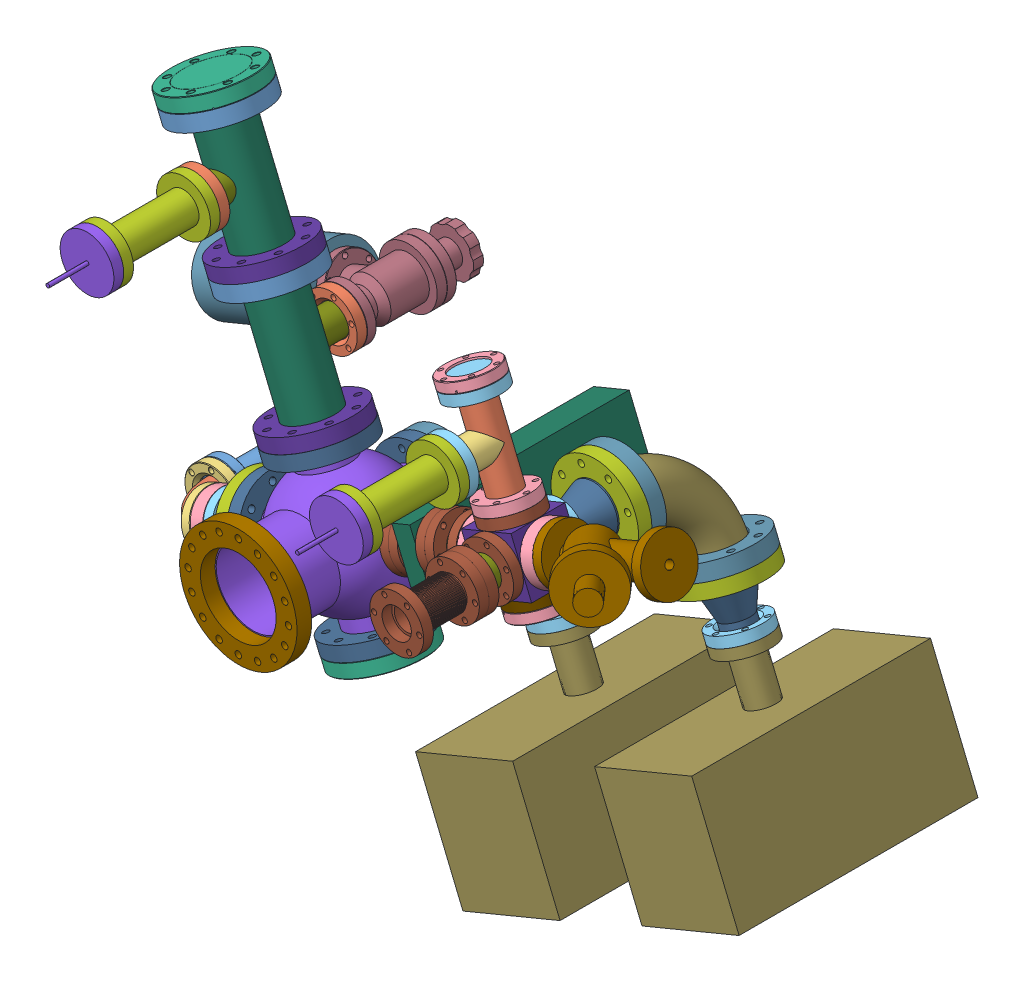
SolidWorks assembly Oven_BEC5_v2, configuration Default. Lengths in mm.
Overall size (747.25 862.61 620.88).
121 component instances, 43 part files, 72 mates.
Components (placement in the parent):
- mdc 275 halfnipple-1: mdc 275 halfnipple [Default] at (-24.8274 -18.3346 25.5574) size (69.34 69.34 62.48)
- L275-403502-6: L275-403502 [Default] at (27.1869 1.5159 24.2874) x (-0.923728 -0.383049 0) z (0 0 -1) size (77.27 39.99 77.27)
- 915002-3: 915002 [Default] at (-24.8274 -18.3346 38.2574) x (0 0 -1) z (1 0 0) size (12.7 69.34 69.34)
- mdc 2.75 doublesided_hole-1: mdc 2.75 doublesided_hole [Default] at (43.4775 8.648 79.5644) x (0.146727 -0.353833 -0.923728) z (0.923728 0.383049 0) size (69.34 69.34 19.05)
- 915002-4: 915002 [Default] at (14.1491 -3.5138 79.5644) x (0.923728 0.383049 0) z (0 0 1) size (12.7 69.34 69.34)
- 100014 (2.75 X 1.5 REC)-1: 100014 (2.75 X 1.5 REC) [Default] at (43.4775 8.648 79.5644) x (0.923728 0.383049 0) z (0 0 1) size (12.7 69.34 69.34)
- red1-402032-001-1: red1-402032-001 [Default] at (97.817 31.1814 79.5644) x (-0.923728 -0.383049 0) z (0 0 1) size (60.1 63.5 63.5)
- 110021 (4.5 X 2.5 NR)-1: 110021 (4.5 X 2.5 NR) [Default] at (97.817 31.1814 79.5644) x (-0.923728 -0.383049 0) z (0 0 1) size (17.27 113.54 113.54)
- custom_sixway_cross-1: custom_sixway_cross [Default] at (189.7246 79.077 65.1716) x (-0.923728 -0.383049 0) z (-0.383049 0.923728 0) size (201.17 247.4 209.3)
  - custom_sixway_tube-1: custom_sixway_tube [Default] at (-1.4041 14.3928 -9.0374) size (170.94 210.82 174.24)
  - 6in_CF_flange-3: 6in_CF_flange [Default] at (-1.4041 157.1408 -9.0374) x (1 0 0) z (0 -1 0) size (152.4 152.4 19.05)
  - 4.5in_CF_flange-1: 4.5in_CF_flange [Default] at (85.7179 14.3928 -9.0374) x (0 -1 0) z (0 0 1) size (114.3 17.53 114.3)
  - 4.5in_CF_flange-2: 4.5in_CF_flange [Default] at (-1.4041 14.3928 78.0846) x (1 0 0) z (0 -1 0) size (114.3 17.53 114.3)
  - 4.5in_CF_flange-3: 4.5in_CF_flange [Default] at (-1.4041 14.3928 -113.6854) x (1 0 0) z (0 -1 0) size (114.3 17.53 114.3)
  - 2.75in_CF_flange-1: 2.75in_CF_flange [Default] at (-97.9241 14.3928 -9.0374) x (0 -1 0) z (0 0 1) size (69.85 12.7 69.85)
  - 4.5in_CF_flange-4: 4.5in_CF_flange [Default] at (-1.4041 -90.2552 -9.0374) size (114.3 17.53 114.3)
- L4-403004_1-3: L4-403004_1 [Default] at (231.0174 -16.8357 -129.9856) x (0 0 1) z (-0.923728 -0.383049 0) size (161.67 161.67 113.54)
  - 403004-001_1-1: 403004-001_1 [Default] at origin size (128.92 128.92 67.08)
  - 100021 (4.5 X 2.5 R)_2-1: 100021 (4.5 X 2.5 R)_2 [Default] at (92.202 95.377 0) x (1 0 0) z (0 0 -1) size (19.05 113.54 113.54)
    - 100021 (4.5 X 2.5 INS)_2-1: 100021 (4.5 X 2.5 INS)_2 [Default] at origin size (12.04 82.3 82.3)
    - 100021 (4.5 X 2.5 REC)_2-1: 100021 (4.5 X 2.5 REC)_2 [Default] at (-6.35 0 0) x (1 0 0) z (0 0 -1) size (19.05 113.54 113.54)
  - 100021 (4.5 X 2.5 R)_2-2: 100021 (4.5 X 2.5 R)_2 [Default] at (0 3.175 0) x (0 -1 0) z (0 0 -1) size (19.05 113.54 113.54)
    - 100021 (4.5 X 2.5 INS)_2-1: 100021 (4.5 X 2.5 INS)_2 [Default] at origin size (12.04 82.3 82.3)
    - 100021 (4.5 X 2.5 REC)_2-1: 100021 (4.5 X 2.5 REC)_2 [Default] at (-6.35 0 0) x (1 0 0) z (0 0 -1) size (19.05 113.54 113.54)
- gatevalve-1: gatevalve [Default] at (298.9549 11.514 55.3656) x (0.383049 -0.923728 0) z (0.923728 0.383049 0) size (88.9 280.54 50.84)
  - gatevalve_body-1: gatevalve_body [Default] at (-95.213 2.8522 48.3049) size (88.9 277.88 50.04)
  - 2.75in_CF_flange-3: 2.75in_CF_flange [Default] at (-95.213 -24.1988 73.7492) x (1 0 0) z (0 1 0) size (69.85 12.7 69.85)
  - 2.75in_CF_flange-4: 2.75in_CF_flange [Default] at (-95.213 -24.1988 35.6049) x (-1 0 0) z (0 -1 0) size (69.85 12.7 69.85)
- minilength_nipple-1: minilength_nipple [Default] at (349.6703 127.2966 78.7528) x (0.383049 -0.923728 0) z (0 0 1) size (69.85 44.45 69.85)
  - minilength_nipple_tube-1: minilength_nipple_tube [Default] at (-7.6879 4.7765 0.8117) size (38.1 19.05 38.1)
  - 2.75in_CF_flange-3: 2.75in_CF_flange [Default] at (-7.6879 14.3015 0.8117) size (69.85 12.7 69.85)
  - 2.75in_CF_flange-4: 2.75in_CF_flange [Default] at (-7.6879 -17.4485 0.8117) size (69.85 12.7 69.85)
- mdc 2.75 doublesided_hole-4: mdc 2.75 doublesided_hole [Default] at (371.6676 144.741 79.5644) x (0.146727 -0.353833 0.923728) z (-0.923728 -0.383049 0) size (69.34 69.34 19.05)
- mdc 2.75 doublesided_hole-5: mdc 2.75 doublesided_hole [Default] at (453.787 178.7941 79.5644) x (0.146727 -0.353833 0.923728) z (-0.923728 -0.383049 0) size (69.34 69.34 19.05)
- six way cube-1: six way cube [Default] at (421.5258 165.4161 79.5644) x (0 0 1) z (-0.923728 -0.383049 0) size (69.85 69.85 69.85)
- 2.75in  window mdc-1: 2.75in  window mdc [Default] at (439.7685 121.4235 79.5644) x (0.853273 0.353833 0.383049) z (-0.383049 0.923728 0) size (69.34 69.34 12.7)
  - Part3^2.75in  window mdc-1: Part3^2.75in  window mdc [Default] at origin size (69.34 69.34 12.7) (virtual)
  - Part4^2.75in  window mdc-1: Part4^2.75in  window mdc [Default] at (0 0 12.7) size (38.1 38.1 2.67) (virtual)
- T275-404002_a-1: T275-404002_a [Default] at (357.4671 319.8944 79.5644) x (0.923728 0.383049 0) z (0.383049 -0.923728 0) size (69.34 97.13 124.92)
  - 404002-001-1: 404002-001 [Default] at origin size (38.1 38.1 114.3)
  - 404002-002-1: 404002-002 [Default] at (0 0 57.15) x (-1 0 0) z (0 1 0) size (38.1 38.1 58.53)
  - 110014 (2.75 X 1.5 NR)_1-1: 110014 (2.75 X 1.5 NR)_1 [Default] at (0 0 113.2586) x (0 0 1) z (-1 0 0) size (12.7 69.34 69.34)
  - 100014 (2.75 X 1.5 R)-1: 100014 (2.75 X 1.5 R) [Default] at (0 62.4586 57.15) x (0 -1 0) z (1 0 0) size (12.7 69.34 69.34)
    - 100014 (2.75 X 1.5 REC)_1-1: 100014 (2.75 X 1.5 REC)_1 [Default] at origin size (12.7 69.34 69.34)
    - 100014 (2.75 X 1.5 INS)-1: 100014 (2.75 X 1.5 INS) [Default] at (1.17 0 0) x (1 0 0) z (0 0.994423 -0.105464) size (6.96 48.1 48.1)
  - 100014 (2.75 X 1.5 R)-2: 100014 (2.75 X 1.5 R) [Default] at (0 0 -5.3086) x (0 0 1) z (-1 0 0) size (12.7 69.34 69.34)
    - 100014 (2.75 X 1.5 REC)_1-1: 100014 (2.75 X 1.5 REC)_1 [Default] at origin size (12.7 69.34 69.34)
    - 100014 (2.75 X 1.5 INS)-1: 100014 (2.75 X 1.5 INS) [Default] at (1.17 0 0) x (1 0 0) z (0 0.994423 -0.105464) size (6.96 48.1 48.1)
- 2.75in_CF_flange-1: 2.75in_CF_flange [Default] at (403.2831 209.4086 79.5644) x (-0.923728 -0.383049 0) z (0 0 1) size (69.85 12.7 69.85)
- nipple 2.75 mdc-2: nipple 2.75 mdc [Default] at (379.3584 267.1034 142.023) x (1 0 0) z (0 -1 0) size (69.85 125.22 69.85)
- ion gauge uhv 24p footprint-2: ion gauge uhv 24p footprint [Default] at (379.3584 267.1034 279.945) x (1 0 0) z (0 1 0) size (69.85 147.62 69.85)
- valve mdc inline all metal small-1: valve mdc inline all metal small [Default] at (470.2109 185.6047 79.5644) x (-0.383049 0.923728 0) z (0 0 -1) size (75.44 172.37 161.4)
- 402032-1: 402032 [Default] at (421.5258 165.4161 -20.7656) x (0 0 1) z (-1 0 0) size (74.93 113.54 113.54)
  - 402032-001-1: 402032-001 [Default] at origin size (60.1 63.5 63.5)
  - 110021 (4.5 X 2.5 NR)-1: 110021 (4.5 X 2.5 NR) [Default] at (-9.525 0 0) size (17.27 113.54 113.54)
  - 100014 (2.75 X 1.5 R)-1: 100014 (2.75 X 1.5 R) [Default] at (65.405 0 0) x (-1 0 0) z (0 0 -1) size (12.7 69.34 69.34)
    - 100014 (2.75 X 1.5 REC)_1-1: 100014 (2.75 X 1.5 REC)_1 [Default] at origin size (12.7 69.34 69.34)
    - 100014 (2.75 X 1.5 INS)-1: 100014 (2.75 X 1.5 INS) [Default] at (1.17 0 0) x (1 0 0) z (0 0.994423 -0.105464) size (6.96 48.1 48.1)
- L4-403004_1-4: L4-403004_1 [Default] at (421.5258 165.4161 -39.8156) x (0.383049 -0.923728 0) z (0.923728 0.383049 0) size (161.67 161.67 113.54)
  - 403004-001_1-1: 403004-001_1 [Default] at origin size (128.92 128.92 67.08)
  - 100021 (4.5 X 2.5 R)_2-1: 100021 (4.5 X 2.5 R)_2 [Default] at (92.202 95.377 0) x (1 0 0) z (0 0 -1) size (19.05 113.54 113.54)
    - 100021 (4.5 X 2.5 INS)_2-1: 100021 (4.5 X 2.5 INS)_2 [Default] at origin size (12.04 82.3 82.3)
    - 100021 (4.5 X 2.5 REC)_2-1: 100021 (4.5 X 2.5 REC)_2 [Default] at (-6.35 0 0) x (1 0 0) z (0 0 -1) size (19.05 113.54 113.54)
  - 100021 (4.5 X 2.5 R)_2-2: 100021 (4.5 X 2.5 R)_2 [Default] at (0 3.175 0) x (0 -1 0) z (0 0 -1) size (19.05 113.54 113.54)
    - 100021 (4.5 X 2.5 INS)_2-1: 100021 (4.5 X 2.5 INS)_2 [Default] at origin size (12.04 82.3 82.3)
    - 100021 (4.5 X 2.5 REC)_2-1: 100021 (4.5 X 2.5 REC)_2 [Default] at (-6.35 0 0) x (1 0 0) z (0 0 -1) size (19.05 113.54 113.54)
- minilength_nipple-2: minilength_nipple [Default] at (429.2137 166.2277 131.9379) x (1 0 0) z (0 -1 0) size (69.85 44.45 69.85)
  - minilength_nipple_tube-1: minilength_nipple_tube [Default] at (-7.6879 4.7765 0.8117) size (38.1 19.05 38.1)
  - 2.75in_CF_flange-3: 2.75in_CF_flange [Default] at (-7.6879 14.3015 0.8117) size (69.85 12.7 69.85)
  - 2.75in_CF_flange-4: 2.75in_CF_flange [Default] at (-7.6879 -17.4485 0.8117) size (69.85 12.7 69.85)
- Bellow_2.75in_CF-1: Bellow_2.75in_CF [Default] at (449.3378 155.3944 206.3015) x (1 0 0) z (0 1 0) size (96.68 84.96 96.68)
  - 2.75in_bellow_tube-1: 2.75in_bellow_tube [Default] at (-27.8121 6.8508 10.0217) size (43.18 63.5 43.18)
  - 2.75in_CF_flange-1: 2.75in_CF_flange [Default] at (-27.8121 47.3621 10.0217) x (-0.837169 0 -0.546944) z (-0.546944 0 0.837169) size (69.85 12.7 69.85)
  - 2.75in_CF_flange-2: 2.75in_CF_flange [Default] at (-27.8121 -24.8992 10.0217) x (-0.837169 0 -0.546944) z (-0.546944 0 0.837169) size (69.85 12.7 69.85)
- 404002-001_1-1: 404002-001_1 [Default] at (115.1337 -161.6135 43.2434)
- 402032-2: 402032 [Default] at (238.3145 -34.4327 -129.9856) x (0.383049 -0.923728 0) z (0 0 1) size (74.93 113.54 113.54)
  - 402032-001-1: 402032-001 [Default] at origin size (60.1 63.5 63.5)
  - 110021 (4.5 X 2.5 NR)-1: 110021 (4.5 X 2.5 NR) [Default] at (-9.525 0 0) size (17.27 113.54 113.54)
  - 100014 (2.75 X 1.5 R)-1: 100014 (2.75 X 1.5 R) [Default] at (65.405 0 0) x (-1 0 0) z (0 0 -1) size (12.7 69.34 69.34)
    - 100014 (2.75 X 1.5 REC)_1-1: 100014 (2.75 X 1.5 REC)_1 [Default] at origin size (12.7 69.34 69.34)
    - 100014 (2.75 X 1.5 INS)-1: 100014 (2.75 X 1.5 INS) [Default] at (1.17 0 0) x (1 0 0) z (0 0.994423 -0.105464) size (6.96 48.1 48.1)
- 402032-3: 402032 [Default] at (465.3569 59.7166 -135.1926) x (0.383049 -0.923728 0) z (0 0 1) size (74.93 113.54 113.54)
  - 402032-001-1: 402032-001 [Default] at origin size (60.1 63.5 63.5)
  - 110021 (4.5 X 2.5 NR)-1: 110021 (4.5 X 2.5 NR) [Default] at (-9.525 0 0) size (17.27 113.54 113.54)
  - 100014 (2.75 X 1.5 R)-1: 100014 (2.75 X 1.5 R) [Default] at (65.405 0 0) x (-1 0 0) z (0 0 -1) size (12.7 69.34 69.34)
    - 100014 (2.75 X 1.5 REC)_1-1: 100014 (2.75 X 1.5 REC)_1 [Default] at origin size (12.7 69.34 69.34)
    - 100014 (2.75 X 1.5 INS)-1: 100014 (2.75 X 1.5 INS) [Default] at (1.17 0 0) x (1 0 0) z (0 0.994423 -0.105464) size (6.96 48.1 48.1)
- Ion_Pump_40ls-1: Ion_Pump_40ls [Default] at (307.7138 -325.5851 -18.3452) x (0 0 -1) z (-0.383049 0.923728 0) size (309.88 136.4 230.12)
- Ion_Pump_40ls-2: Ion_Pump_40ls [Default] at (622.3618 -195.1078 -246.8329) x (0 0 1) z (-0.383049 0.923728 0) size (309.88 136.4 230.12)
- nipple 2.75 mdc-3: nipple 2.75 mdc [Default] at (55.8874 405.4928 267.245) x (1 0 0) z (0 1 0) size (69.85 125.22 69.85)
- ion gauge uhv 24p footprint-3: ion gauge uhv 24p footprint [Default] at (55.8874 405.4928 279.945) x (1 0 0) z (0 1 0) size (69.85 147.62 69.85)
- angle valve 1.5 inch 310029 mdc-3: angle valve 1.5 inch 310029 mdc [Default] at (121.5611 247.1196 -83.6052) x (-0.923728 -0.383049 0) z (0.383049 -0.923728 0) size (100.2 160.92 75.44)
- turbo pump footpring-2: turbo pump footpring [Default] at (63.8429 223.1852 -46.318) x (-0.383049 0.923728 0) z (0 0 1) size (91.44 162.05 91.44)
- 404048-1: 404048 [Default] at (92.3728 317.5077 79.5644) x (-0.923728 -0.383049 0) z (0.383049 -0.923728 0) size (113.54 119.23 171.45)
  - 404048-001-1: 404048-001 [Default] at origin size (63.5 63.5 152.4)
  - 404048-002-1: 404048-002 [Default] at (0 0 76.2) x (1 0 0) z (0 1 0) size (38.1 38.1 35.24)
  - 110021 (4.5 X 2.5 NR)_1-1: 110021 (4.5 X 2.5 NR)_1 [Default] at (0 0 161.925) x (0 0 -1) z (1 0 0) size (17.27 113.54 113.54)
  - 100021 (4.5 X 2.5 R)-1: 100021 (4.5 X 2.5 R) [Default] at (0 0 3.175) x (0 0 -1) z (1 0 0) size (19.05 113.54 113.54)
    - 100021 (4.5 X 2.5 INS)-1: 100021 (4.5 X 2.5 INS) [Default] at origin size (12.04 82.3 82.3)
    - 100021 (4.5 X 2.5 REC)-1: 100021 (4.5 X 2.5 REC) [Default] at (-6.35 0 0) x (1 0 0) z (0 0 -1) size (19.05 113.54 113.54)
  - 100014 (2.75 X 1.5 R)_2-1: 100014 (2.75 X 1.5 R)_2 [Default] at (0 62.4586 76.2) x (0 -1 0) z (1 0 0) size (12.7 69.34 69.34)
    - 100014 (2.75 X 1.5 REC)_3-1: 100014 (2.75 X 1.5 REC)_3 [Default] at origin size (12.7 69.34 69.34)
    - 100014 (2.75 X 1.5 INS)_2-1: 100014 (2.75 X 1.5 INS)_2 [Default] at (1.17 0 0) x (1 0 0) z (0 0.994423 -0.105464) size (6.96 48.1 48.1)
- 404048-2: 404048 [Default] at (26.6991 475.8809 79.5644) x (0.923728 0.383049 0) z (0.383049 -0.923728 0) size (113.54 119.23 171.45)
  - 404048-001-1: 404048-001 [Default] at origin size (63.5 63.5 152.4)
  - 404048-002-1: 404048-002 [Default] at (0 0 76.2) x (1 0 0) z (0 1 0) size (38.1 38.1 35.24)
  - 110021 (4.5 X 2.5 NR)_1-1: 110021 (4.5 X 2.5 NR)_1 [Default] at (0 0 161.925) x (0 0 -1) z (1 0 0) size (17.27 113.54 113.54)
  - 100021 (4.5 X 2.5 R)-1: 100021 (4.5 X 2.5 R) [Default] at (0 0 3.175) x (0 0 -1) z (1 0 0) size (19.05 113.54 113.54)
    - 100021 (4.5 X 2.5 INS)-1: 100021 (4.5 X 2.5 INS) [Default] at origin size (12.04 82.3 82.3)
    - 100021 (4.5 X 2.5 REC)-1: 100021 (4.5 X 2.5 REC) [Default] at (-6.35 0 0) x (1 0 0) z (0 0 -1) size (19.05 113.54 113.54)
  - 100014 (2.75 X 1.5 R)_2-1: 100014 (2.75 X 1.5 R)_2 [Default] at (0 62.4586 76.2) x (0 -1 0) z (1 0 0) size (12.7 69.34 69.34)
    - 100014 (2.75 X 1.5 REC)_3-1: 100014 (2.75 X 1.5 REC)_3 [Default] at origin size (12.7 69.34 69.34)
    - 100014 (2.75 X 1.5 INS)_2-1: 100014 (2.75 X 1.5 INS)_2 [Default] at (1.17 0 0) x (1 0 0) z (0 0.994423 -0.105464) size (6.96 48.1 48.1)
- 450002 (2.75 viewport)-1: 450002 (2.75 viewport) [Default] at (447.5845 117.7903 88.5635) x (0.853273 0.353833 0.383049) z (-0.383049 0.923728 0) size (69.34 69.34 12.7)
  - 130094-1: 130094 [Default] at (-8.8308 6.0802 -6.35) size (69.34 69.34 12.7)
  - glass-1: glass [Default] at (-8.8308 6.0802 1.0414) x (-1 0 0) z (0 0 -1) size (44.7 44.7 5.08)
- 450002 (2.75 viewport)-2: 450002 (2.75 viewport) [Default] at (358.385 332.8963 70.5653) x (0.853273 0.353833 -0.383049) z (0.383049 -0.923728 0) size (69.34 69.34 12.7)
  - 130094-1: 130094 [Default] at (-8.8308 6.0802 -6.35) size (69.34 69.34 12.7)
  - glass-1: glass [Default] at (-8.8308 6.0802 1.0414) x (-1 0 0) z (0 0 -1) size (44.7 44.7 5.08)
- 450004-1: 450004 [Default] at (23.0505 484.6794 79.5644) x (0.853273 0.353833 -0.383049) z (0.383049 -0.923728 0) size (113.54 113.54 17.28)
- 450004-2: 450004 [Default] at (234.5687 -25.3996 79.5644) x (0.853273 0.353833 0.383049) z (-0.383049 0.923728 0) size (113.54 113.54 17.28)
Mates (geometry in assembly coordinates):
- Coincident9: coincident anti-aligned: plane of mdc 275 halfnipple-1 through (-24.8274 -18.3346 24.2874) normal (0 0 1); plane of L275-403502-6 through (-25.6042 -20.3753 24.2874) normal (0 0 -1)
- Tangent4: tangent: cylinder of mdc 275 halfnipple-1 through (-24.8274 -18.3346 24.2874) axis (0 0 -1) radius 17.4625; face of L275-403502-6
- Coincident12: coincident anti-aligned: plane of mdc 275 halfnipple-1 through (-24.8274 -18.3346 25.5574) normal (0 0 1); plane of 915002-3 through (-24.8274 -18.3346 25.5574) normal (0 0 -1)
- Coincident14: coincident anti-aligned: plane of mdc 275 halfnipple-1 through (-24.8274 -18.3346 25.5574) normal (0 0 1); plane of 915002-3 through (-24.8274 -18.3346 25.5574) normal (0 0 -1)
- Coincident15: coincident aligned: circle of mdc 275 halfnipple-1; circle of 915002-3
- Coincident16: coincident anti-aligned: plane of L275-403502-6 through (27.1869 1.5159 81.4374) normal (0.923728 0.383049 0); plane of mdc 2.75 doublesided_hole-1 through (27.0536 1.8374 79.5644) normal (-0.923728 -0.383049 0)
- Tangent6: tangent: edge_curve of L275-403502-6; cylinder of mdc 2.75 doublesided_hole-1 through (27.6508 2.0851 79.5644) axis (0.923728 0.383049 0) radius 20.955
- Coincident17: coincident anti-aligned: plane of mdc 2.75 doublesided_hole-1 through (25.8804 1.3509 79.5644) normal (-0.923728 -0.383049 0); plane of 915002-4 through (25.8804 1.3509 79.5644) normal (0.923728 0.383049 0)
- Coincident18: coincident anti-aligned: circle of 915002-4; circle of mdc 2.75 doublesided_hole-1
- Coincident19: coincident anti-aligned: plane of mdc 2.75 doublesided_hole-1 through (42.3043 8.1616 79.5644) normal (0.923728 0.383049 0); plane of ? through (49.2852 -8.6729 79.5644) normal (-0.923728 -0.383049 0)
- Concentric1: concentric anti-aligned: cylinder of mdc 2.75 doublesided_hole-1 through (41.7071 7.9139 79.5644) axis (0.923728 0.383049 0) radius 20.955; cylinder of ? through (48.17 10.5939 79.5644) axis (-0.923728 -0.383049 0) radius 19.05
- Coincident20: coincident anti-aligned: plane of mdc 2.75 doublesided_hole-1 through (43.4775 8.648 79.5644) normal (0.923728 0.383049 0); plane of 100014 (2.75 X 1.5 REC)-1 through (32.2261 35.7809 79.5644) normal (-0.923728 -0.383049 0)
- Concentric2: concentric anti-aligned: cylinder of 100014 (2.75 X 1.5 REC)-1 through (46.9969 10.1074 79.5644) axis (0.923728 0.383049 0) radius 24.0754; cylinder of ? through (48.17 10.5939 79.5644) axis (-0.923728 -0.383049 0) radius 19.05
- Coincident22: coincident anti-aligned: plane of ? through (109.6626 2.6156 79.5644) normal (0.923728 0.383049 0); plane of custom_sixway_cross-1/4.5in_CF_flange-1 through (97.817 31.1814 79.5644) normal (-0.923728 -0.383049 0)
- Coincident23: coincident aligned: circle of ?; circle of custom_sixway_cross-1/4.5in_CF_flange-1
- Coincident24: coincident anti-aligned: plane of ? through (116.5949 -14.1016 79.5644) normal (0.923728 0.383049 0); plane of custom_sixway_cross-1/4.5in_CF_flange-1 through (97.817 31.1814 79.5644) normal (-0.923728 -0.383049 0)
- Concentric3: concentric aligned: cylinder of ? through (93.4178 29.3571 79.5644) axis (-0.923728 -0.383049 0) radius 31.75; cylinder of ? through (92.8774 29.1331 79.5644) axis (-0.923728 -0.383049 0) radius 30.1625
- Parallel6: parallel aligned: plane of mdc 275 halfnipple-1 through (-24.8274 -18.3346 -36.9266) normal (0 0 -1); plane of custom_sixway_cross-1/4.5in_CF_flange-4 through (194.4833 71.2667 -25.0836) normal (0 0 -1)
- Coincident43: coincident anti-aligned: plane of custom_sixway_cross-1/4.5in_CF_flange-4 through (194.4833 71.2667 -25.0836) normal (0 0 -1); plane of L4-403004_1-3/100021 (4.5 X 2.5 R)_2-1/100021 (4.5 X 2.5 REC)_2-1 through (175.7055 116.5497 -25.0836) normal (0 0 1)
- Concentric14: concentric anti-aligned: circle of custom_sixway_cross-1/4.5in_CF_flange-4; circle of L4-403004_1-3/100021 (4.5 X 2.5 R)_2-1/100021 (4.5 X 2.5 INS)_2-1
- Coincident48: coincident anti-aligned: plane of custom_sixway_cross-1/2.75in_CF_flange-1 through (283.6416 108.2386 79.5644) normal (0.923728 0.383049 0); plane of gatevalve-1/2.75in_CF_flange-4 through (283.6416 108.2386 79.5644) normal (-0.923728 -0.383049 0)
- Coincident49: coincident aligned: circle of custom_sixway_cross-1/2.75in_CF_flange-1; circle of gatevalve-1/2.75in_CF_flange-4
- Coincident51: coincident anti-aligned: plane of gatevalve-1/2.75in_CF_flange-3 through (330.6079 127.7145 79.5644) normal (0.923728 0.383049 0); plane of minilength_nipple-1/2.75in_CF_flange-4 through (330.6079 127.7145 79.5644) normal (-0.923728 -0.383049 0)
- Coincident52: coincident anti-aligned: circle of gatevalve-1/2.75in_CF_flange-3; circle of minilength_nipple-1/2.75in_CF_flange-4
- Coincident53: coincident anti-aligned: plane of minilength_nipple-1/2.75in_CF_flange-3 through (371.6676 144.741 79.5644) normal (0.923728 0.383049 0); plane of mdc 2.75 doublesided_hole-4 through (371.6676 144.741 79.5644) normal (-0.923728 -0.383049 0)
- Concentric17: concentric aligned: circle of minilength_nipple-1/2.75in_CF_flange-3; circle of mdc 2.75 doublesided_hole-4
- Coincident54: coincident anti-aligned: plane of mdc 2.75 doublesided_hole-4 through (389.2646 152.0381 79.5644) normal (0.923728 0.383049 0); plane of six way cube-1 through (375.8866 184.2993 44.6394) normal (-0.923728 -0.383049 0)
- Concentric18: concentric anti-aligned: circle of mdc 2.75 doublesided_hole-4; circle of six way cube-1
- Parallel14: parallel aligned: plane of custom_sixway_cross-1/6in_CF_flange-3 through (194.4833 71.2667 222.3124) normal (0 0 1); plane of six way cube-1 through (402.6426 119.7769 114.4894) normal (0 0 1)
- Coincident56: coincident anti-aligned: plane of mdc 2.75 doublesided_hole-5 through (453.787 178.7941 79.5644) normal (-0.923728 -0.383049 0); plane of six way cube-1 through (440.409 211.0553 44.6394) normal (0.923728 0.383049 0)
- Coincident57: coincident aligned: circle of mdc 2.75 doublesided_hole-5; circle of six way cube-1
- Coincident58: coincident anti-aligned: plane of six way cube-1 through (402.6426 119.7769 44.6394) normal (0.383049 -0.923728 0); plane of 2.75in  window mdc-1/Part3^2.75in  window mdc-1 through (434.9038 133.1549 79.5644) normal (-0.383049 0.923728 0)
- Concentric19: concentric aligned: circle of six way cube-1; circle of 2.75in  window mdc-1/Part3^2.75in  window mdc-1
- Coincident59: coincident anti-aligned: plane of six way cube-1 through (375.8866 184.2993 44.6394) normal (-0.383049 0.923728 0); plane of 2.75in_CF_flange-1 through (408.1478 197.6773 79.5644) normal (0.383049 -0.923728 0)
- Concentric20: concentric anti-aligned: circle of six way cube-1; circle of 2.75in_CF_flange-1
- Coincident60: coincident anti-aligned: plane of T275-404002_a-1/110014 (2.75 X 1.5 NR)_1-1 through (403.2831 209.4086 50.1539) normal (0.383049 -0.923728 0); plane of 2.75in_CF_flange-1 through (403.2831 209.4086 79.5644) normal (-0.383049 0.923728 0)
- Concentric21: concentric anti-aligned: circle of T275-404002_a-1/110014 (2.75 X 1.5 NR)_1-1; circle of 2.75in_CF_flange-1
- Coincident63: coincident anti-aligned: plane of nipple 2.75 mdc-2 through (379.3584 267.1034 267.245) normal (0 0 1); plane of ion gauge uhv 24p footprint-2 through (379.3584 267.1034 267.245) normal (0 0 -1)
- Concentric23: concentric anti-aligned: cylinder of nipple 2.75 mdc-2 through (379.3584 267.1034 267.245) axis (0 0 -1) radius 17.526; cylinder of ion gauge uhv 24p footprint-2 through (379.3584 267.1034 183.1202) axis (0 0 1) radius 16.637
- Coincident65: coincident anti-aligned: plane of mdc 2.75 doublesided_hole-5 through (470.2109 185.6047 79.5644) normal (0.923728 0.383049 0); plane of valve mdc inline all metal small-1 through (470.2109 185.6047 79.5644) normal (-0.923728 -0.383049 0)
- Concentric25: concentric aligned: circle of mdc 2.75 doublesided_hole-5; circle of valve mdc inline all metal small-1
- Angle1: planar angle = 0.785398 rad aligned: plane of valve mdc inline all metal small-1 through (593.8073 236.8573 167.8974) normal (0.653174 0.270857 0.707107); plane of nipple 2.75 mdc-2 through (379.3584 267.1034 154.723) normal (0 0 1)
- Coincident68: coincident anti-aligned: plane of 402032-1/110021 (4.5 X 2.5 NR)-1 through (421.5258 214.4381 -30.2906) normal (0 0 -1); plane of L4-403004_1-4/100021 (4.5 X 2.5 R)_2-2/100021 (4.5 X 2.5 REC)_2-1 through (440.3036 120.1331 -30.2906) normal (0 0 1)
- Concentric27: concentric anti-aligned: circle of 402032-1/110021 (4.5 X 2.5 NR)-1; circle of L4-403004_1-4/100021 (4.5 X 2.5 R)_2-2/100021 (4.5 X 2.5 REC)_2-1
- Parallel16: parallel aligned: plane of 2.75in  window mdc-1/Part3^2.75in  window mdc-1 through (439.7685 121.4235 79.5644) normal (0.383049 -0.923728 0); plane of L4-403004_1-4/100021 (4.5 X 2.5 R)_2-1/100021 (4.5 X 2.5 REC)_2-1 through (461.7084 68.5152 -184.2146) normal (0.383049 -0.923728 0)
- Coincident72: coincident anti-aligned: plane of six way cube-1 through (402.6426 119.7769 114.4894) normal (0 0 1); plane of minilength_nipple-2/2.75in_CF_flange-4 through (421.5258 165.4161 114.4894) normal (0 0 -1)
- Concentric29: concentric aligned: circle of six way cube-1; circle of minilength_nipple-2/2.75in_CF_flange-4
- Coincident74: coincident anti-aligned: plane of minilength_nipple-2/2.75in_CF_flange-3 through (421.5258 165.4161 158.9394) normal (0 0 1); plane of Bellow_2.75in_CF-1/2.75in_CF_flange-1 through (421.5258 165.4161 158.9394) normal (0 0 -1)
- Coincident75: coincident aligned: circle of minilength_nipple-2/2.75in_CF_flange-3; circle of Bellow_2.75in_CF-1/2.75in_CF_flange-1
- Coincident77: coincident anti-aligned: plane of L4-403004_1-3/100021 (4.5 X 2.5 R)_2-2/100021 (4.5 X 2.5 REC)_2-1 through (234.6659 -25.6342 -80.9636) normal (0.383049 -0.923728 0); plane of 402032-2/110021 (4.5 X 2.5 NR)-1 through (279.9489 -6.8564 -129.9856) normal (-0.383049 0.923728 0)
- Concentric30: concentric anti-aligned: circle of L4-403004_1-3/100021 (4.5 X 2.5 R)_2-2/100021 (4.5 X 2.5 INS)_2-1; circle of 402032-2/110021 (4.5 X 2.5 NR)-1
- Coincident80: coincident anti-aligned: plane of L4-403004_1-4/100021 (4.5 X 2.5 R)_2-1/100021 (4.5 X 2.5 REC)_2-1 through (461.7084 68.5152 -184.2146) normal (0.383049 -0.923728 0); plane of 402032-3/110021 (4.5 X 2.5 NR)-1 through (506.9914 87.293 -135.1926) normal (-0.383049 0.923728 0)
- Coincident81: coincident anti-aligned: circle of L4-403004_1-4/100021 (4.5 X 2.5 R)_2-1/100021 (4.5 X 2.5 REC)_2-1; circle of 402032-3/110021 (4.5 X 2.5 NR)-1
- Parallel19: parallel aligned: plane of custom_sixway_cross-1/6in_CF_flange-3 through (194.4833 71.2667 222.3124) normal (0 0 1); plane of Ion_Pump_40ls-1 through (227.0292 -185.2605 24.9544) normal (0 0 1)
- Parallel20: parallel aligned: plane of Bellow_2.75in_CF-1/2.75in_CF_flange-2 through (421.5258 165.4161 243.9007) normal (0 0 1); plane of Ion_Pump_40ls-2 through (580.0663 -38.864 19.7474) normal (0 0 1)
- Coincident99: coincident anti-aligned: plane of nipple 2.75 mdc-3 through (55.8874 405.4928 267.245) normal (0 0 1); plane of ion gauge uhv 24p footprint-3 through (55.8874 405.4928 267.245) normal (0 0 -1)
- Concentric36: concentric aligned: circle of nipple 2.75 mdc-3; circle of ion gauge uhv 24p footprint-3
- Parallel24: parallel aligned: plane of custom_sixway_cross-1/2.75in_CF_flange-1 through (271.9102 103.3739 79.5644) normal (-0.923728 -0.383049 0); plane of angle valve 1.5 inch 310029 mdc-3 through (63.8429 223.1852 -46.318) normal (-0.923728 -0.383049 0)
- Coincident106: coincident anti-aligned: plane of angle valve 1.5 inch 310029 mdc-3 through (63.8429 223.1852 -46.318) normal (-0.923728 -0.383049 0); plane of turbo pump footpring-2 through (63.8429 223.1852 -46.318) normal (0.923728 0.383049 0)
- Concentric40: concentric anti-aligned: circle of angle valve 1.5 inch 310029 mdc-3; circle of turbo pump footpring-2
- Parallel25: parallel anti-aligned: plane of custom_sixway_cross-1/6in_CF_flange-3 through (194.4833 71.2667 222.3124) normal (0 0 1); plane of 404048-1/100014 (2.75 X 1.5 R)_2-1/100014 (2.75 X 1.5 REC)_3-1 through (110.3098 274.2525 17.1058) normal (0 0 -1)
- Coincident109: coincident anti-aligned: plane of angle valve 1.5 inch 310029 mdc-3 through (121.5611 247.1196 17.1058) normal (0 0 1); plane of 404048-1/100014 (2.75 X 1.5 R)_2-1/100014 (2.75 X 1.5 REC)_3-1 through (110.3098 274.2525 17.1058) normal (0 0 -1)
- Concentric42: concentric anti-aligned: circle of angle valve 1.5 inch 310029 mdc-3; circle of 404048-1/100014 (2.75 X 1.5 R)_2-1/100014 (2.75 X 1.5 REC)_3-1
- Parallel26: parallel aligned: plane of custom_sixway_cross-1/6in_CF_flange-3 through (194.4833 71.2667 222.3124) normal (0 0 1); plane of 404048-2/100014 (2.75 X 1.5 R)_2-1/100014 (2.75 X 1.5 REC)_3-1 through (44.636 432.6256 142.023) normal (0 0 1)
- Coincident113: coincident anti-aligned: plane of nipple 2.75 mdc-3 through (55.8874 405.4928 142.023) normal (0 0 -1); plane of 404048-2/100014 (2.75 X 1.5 R)_2-1/100014 (2.75 X 1.5 REC)_3-1 through (44.636 432.6256 142.023) normal (0 0 1)
- Concentric44: concentric anti-aligned: cylinder of nipple 2.75 mdc-3 through (55.8874 405.4928 154.723) axis (0 0 -1) radius 34.925; circle of 404048-2/100014 (2.75 X 1.5 R)_2-1/100014 (2.75 X 1.5 REC)_3-1
- Coincident115: coincident anti-aligned: plane of 2.75in  window mdc-1/Part3^2.75in  window mdc-1 through (439.7685 121.4235 79.5644) normal (0.383049 -0.923728 0); plane of 450002 (2.75 viewport)-1/130094-1 through (439.7685 121.4235 79.5644) normal (-0.383049 0.923728 0)
- Concentric45: concentric anti-aligned: circle of 2.75in  window mdc-1/Part3^2.75in  window mdc-1; circle of 450002 (2.75 viewport)-1/130094-1
- Coincident118: coincident anti-aligned: plane of 404048-2/100021 (4.5 X 2.5 R)-1/100021 (4.5 X 2.5 REC)-1 through (23.0505 484.6794 30.5424) normal (-0.383049 0.923728 0); plane of 450004-1 through (71.49 504.7661 57.8191) normal (0.383049 -0.923728 0)
- Concentric47: concentric anti-aligned: circle of 404048-2/100021 (4.5 X 2.5 R)-1/100021 (4.5 X 2.5 REC)-1; circle of 450004-1
- Coincident120: coincident anti-aligned: plane of custom_sixway_cross-1/4.5in_CF_flange-3 through (234.5687 -25.3996 79.5644) normal (0.383049 -0.923728 0); plane of 450004-2 through (283.0081 -5.3128 101.3097) normal (-0.383049 0.923728 0)
- Concentric48: concentric anti-aligned: circle of custom_sixway_cross-1/4.5in_CF_flange-3; circle of 450004-2
